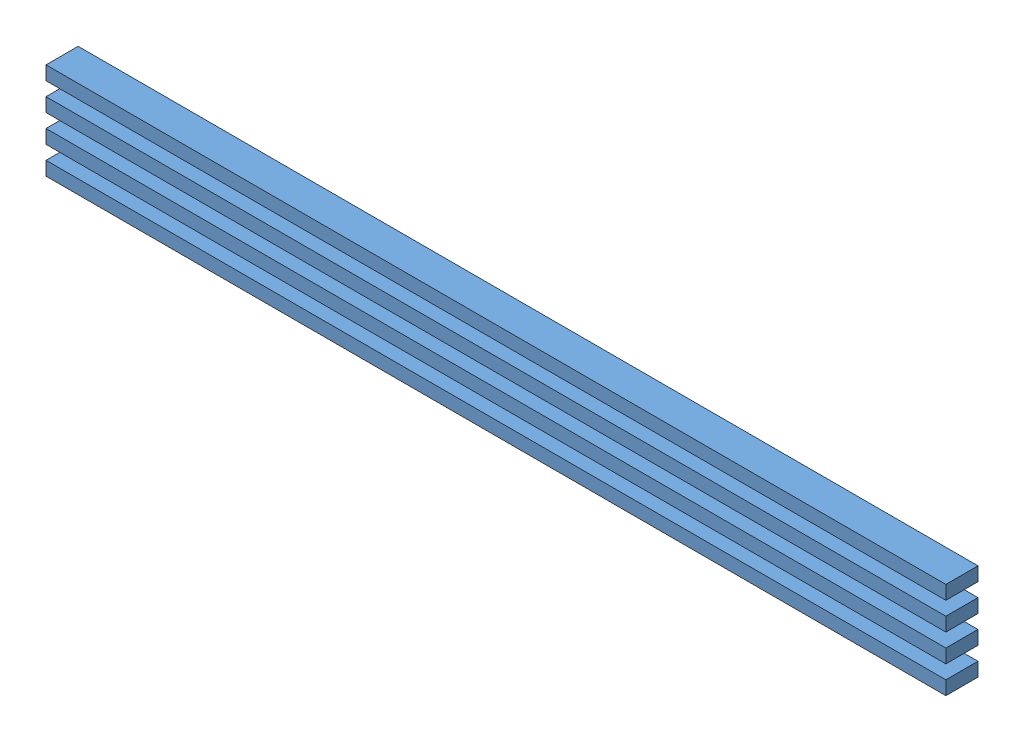
SolidWorks assembly truss_beam_98, configuration Default. Lengths in mm.
Overall size (2489.2 266.7 88.9).
4 component instances, 1 part files, 0 mates.
Components (placement in the parent):
- 2x4x98-1: 2x4x98 [Default] at (-493.8129 1619.7527 2443.6388) size (2489.2 38.1 88.9)
- 2x4x98-2: 2x4x98 [Default] at (-493.8129 1695.9527 2443.6388) size (2489.2 38.1 88.9)
- 2x4x98-3: 2x4x98 [Default] at (-493.8129 1772.1527 2443.6388) size (2489.2 38.1 88.9)
- 2x4x98-4: 2x4x98 [Default] at (-493.8129 1848.3527 2443.6388) size (2489.2 38.1 88.9)
